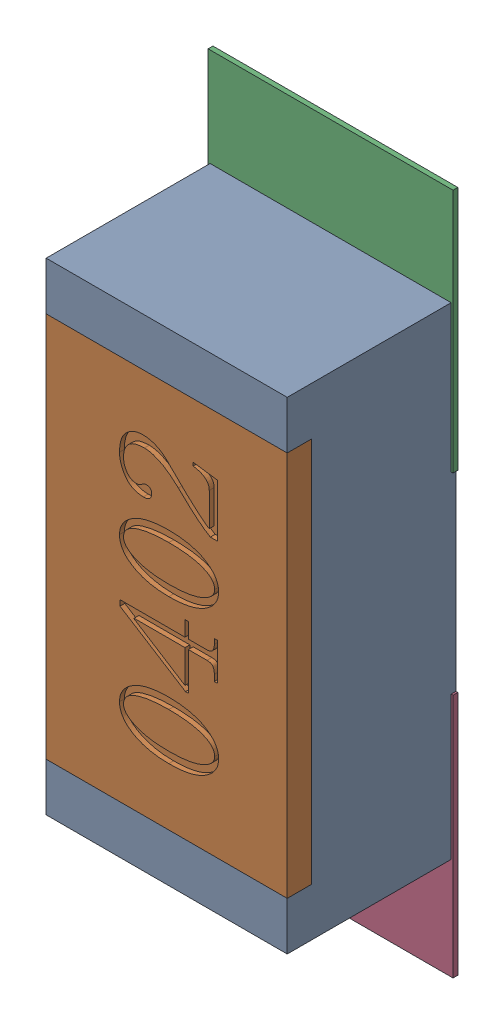
SolidWorks assembly R69, configuration Défaut. Lengths in mm.
Overall size (0.51 1.42 0.35).
5 component instances, 2 part files, 0 mates.
Components (placement in the parent):
- R0402-1: R0402 [Défaut] at (11.1761 -33.9924 0) x (0 1 0) z (0 0 1) size (1 0.5 0.35)
- 6504207776-1: 6504207776 [Défaut] at (11.176 -33.5424 0) size (0.51 0.51 0.01)
  - Extruded-1: Extruded [Défaut] at origin size (0.51 0.51 0.01)
- 6504207776-2: 6504207776 [Défaut] at (11.176 -34.4495 0) size (0.51 0.51 0.01)
  - Extruded-1: Extruded [Défaut] at origin size (0.51 0.51 0.01)
